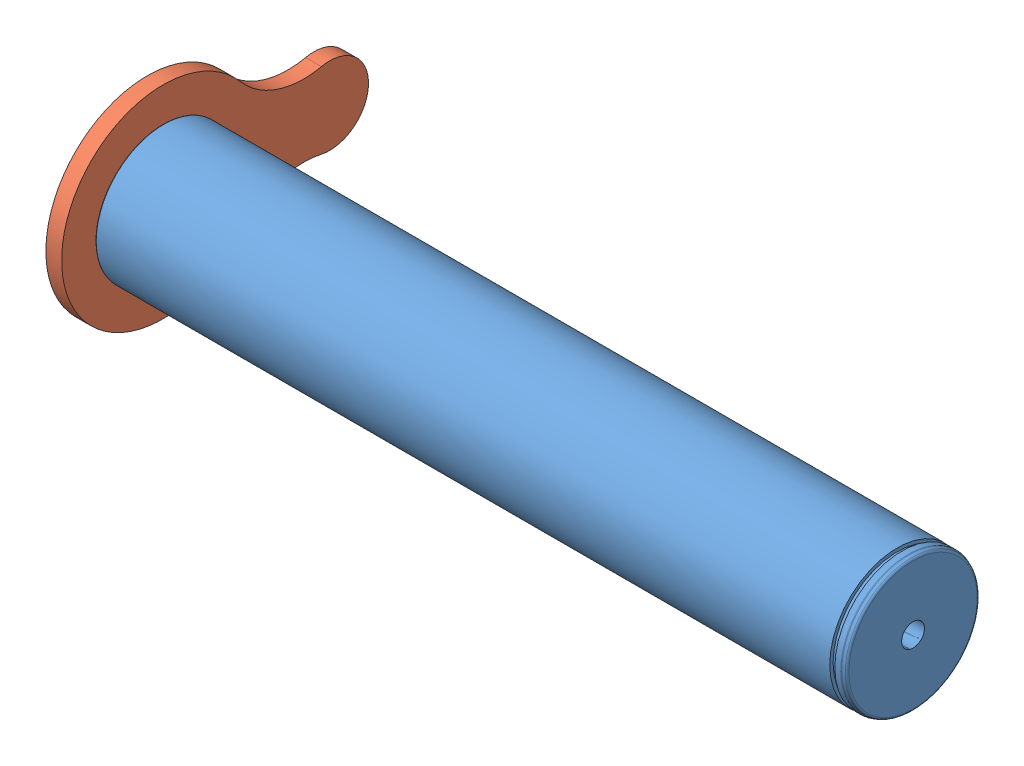
SolidWorks assembly 6344208, configuration Default. Lengths in mm.
Overall size (340 90 136.25).
3 component instances, 3 part files, 6 mates.
Components (placement in the parent):
- 6344209-1: 6344209 [Default] at origin size (338 60 60)
- 6342203-1: 6342203 [Default] at (-170 0 0) x (0 0 -1) z (1 0 0) size (136.25 90 7)
- Prop1_akselender-1: Prop1_akselender [Default] at (-171.1732 0 0) (suppressed, hidden)
Mates (geometry in assembly coordinates):
- Coincident5: coincident anti-aligned: plane of 6344209-1 through (-163 29.6 0) normal (-1 0 0); plane of 6342203-1 through (-163 26.3702 -68.2248) normal (1 0 0)
- Concentric3: concentric aligned: cylinder of 6344209-1 through (-168 0 0) axis (-1 0 0) radius 28; cylinder of 6342203-1 through (-163 0 0) axis (-1 0 0) radius 28.25
- Parallel3: parallel aligned: plane of 6342203-1 through (-170 0 0) normal (0 1 0); plane of assembly through (0 0 0) normal (0 1 0)
- Concentric4: concentric aligned: cylinder of 6344209-1 through (-168 0 0) axis (-1 0 0) radius 5.1; cylinder of assembly through (-171.1732 0 0) axis (-1 0 0) radius 4
- Tangent2: tangent: plane of assembly through (-170 29.9582 -71.8487) normal (-1 0 0)
- Parallel4: parallel: plane of ?; plane of assembly through (0 0 0) normal (0 0 1)
